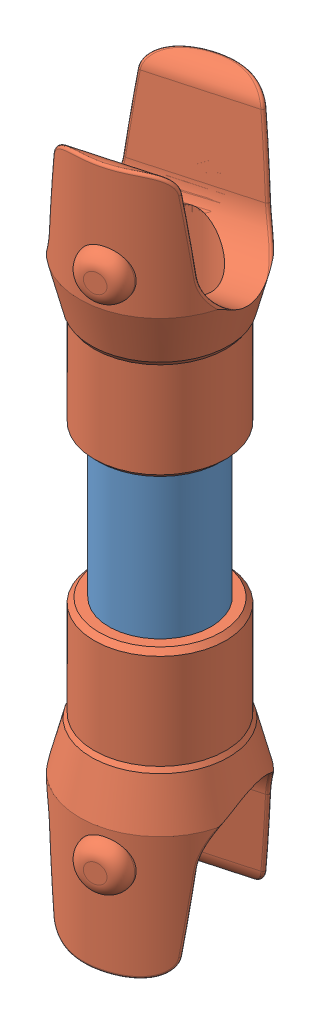
SolidWorks assembly U-JointDoubleMid, configuration Default. Lengths in mm.
Overall size (42.36 158.5 46.32).
3 component instances, 2 part files, 10 mates.
Components (placement in the parent):
- TubeSteering.75-1: TubeSteering.75 [DoubleUJoint] x (1 0 0) z (0 1 0) size (21.34 21.34 56.2)
- U-JointWoodward-1: U-JointWoodward [Default] at (0 62.9 0) x (0 1 0) z (0.963512 0 -0.267666) size (73.55 38.86 33.16)
- U-JointWoodward-2: U-JointWoodward [Default] at (0 -62.9 0) x (0 -1 0) z (0.963512 0 -0.267666) size (73.55 38.86 33.16)
Mates (geometry in assembly coordinates):
- Concentric1: concentric: cylinder of assembly; cylinder of assembly; cylinder of TubeSteering.75-1 through (0 -28.1 0) axis (0 1 0) radius 10.668; cylinder of U-JointWoodward-1 through (0 73.2581 0) axis (0 -1 0) radius 9.525
- Concentric2: concentric: cylinder of assembly; cylinder of assembly; cylinder of TubeSteering.75-1 through (0 -28.1 0) axis (0 1 0) radius 10.668; cylinder of U-JointWoodward-2 through (0 -73.2581 0) axis (0 1 0) radius 9.525
- Parallel1: parallel: line of U-JointWoodward-1 through (2.3891 62.9 8.5999) axis (-0.267666 0 -0.963512); line of U-JointWoodward-2 through (-2.3891 -62.9 -8.5999) axis (0.267666 0 0.963512)
- Distance1: distance = 111.371 mm: line of U-JointWoodward-1 through (1.8605 55.686 8.7295) axis (-0.208452 0 -0.978033); line of U-JointWoodward-2 through (-1.8605 -55.685 -8.7295) axis (0.208452 0 0.978033)
- Distance2: distance = 55.686 mm: point of ?
- Coincident1: coincident: plane of assembly through (0 0 0) normal (0 1 0); plane of TubeSteering.75-1 through (0 0 0) normal (0 1 0); plane of assembly
- Coincident2: coincident: plane of assembly through (0 0 0) normal (0 0 1); plane of TubeSteering.75-1 through (0 0 0) normal (0 0 -1); plane of assembly
- Coincident3: coincident: plane of assembly through (0 0 0) normal (1 0 0); plane of TubeSteering.75-1 through (0 0 0) normal (1 0 0); plane of assembly
- Coincident4: coincident: plane of assembly; plane of assembly; plane of TubeSteering.75-1 through (0 -15.4 0) normal (0 -1 0); plane of U-JointWoodward-2 through (0 -15.4 0) normal (0 1 0)
- Coincident5: coincident: plane of assembly; plane of assembly; plane of TubeSteering.75-1 through (0 15.4 0) normal (0 1 0); plane of U-JointWoodward-1 through (0 15.4 0) normal (0 -1 0)
